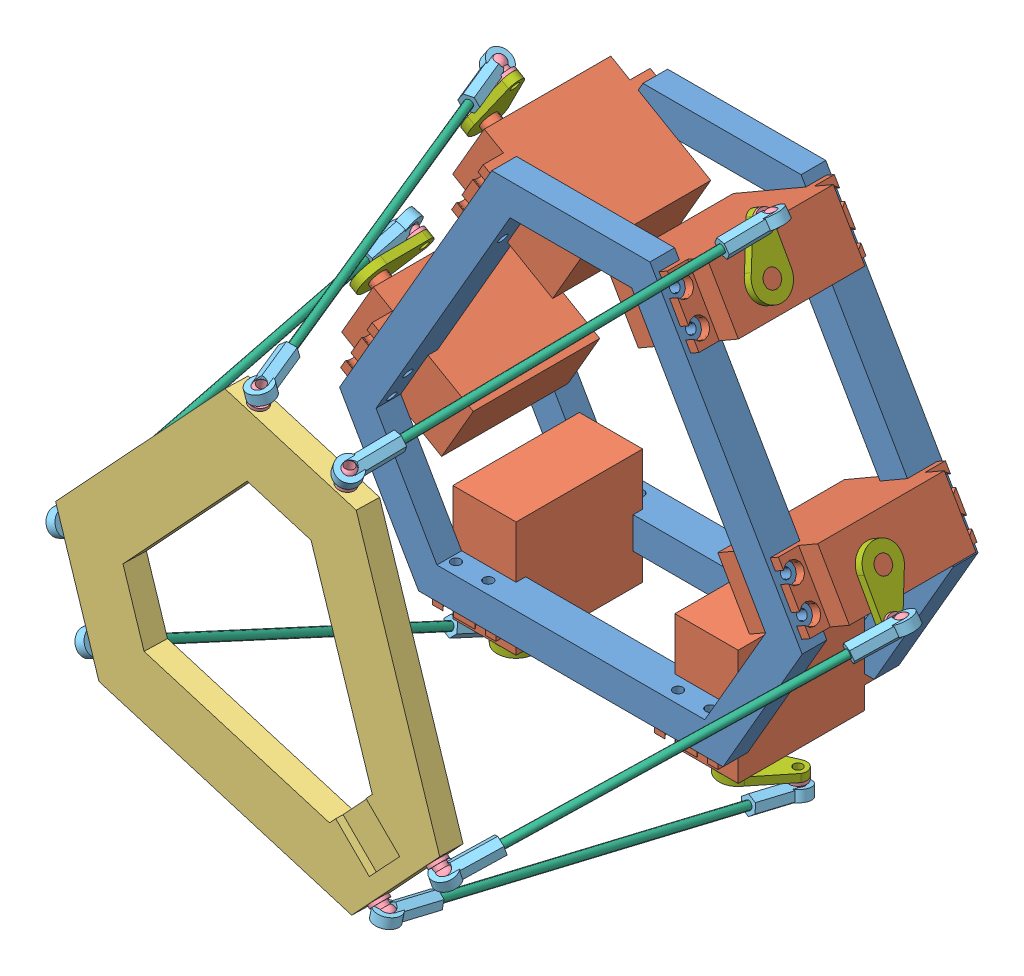
SolidWorks assembly 史都華平台, configuration Default. Lengths in mm.
Overall size (184.22 189.98 155.27).
45 component instances, 7 part files, 100 mates.
Components (placement in the parent):
- 底座-1: 底座 [Default] at (0 0 -7.8) size (146.24 126.65 10.8)
- MG996伺服-1: MG996伺服 [Default] at (-70.2711 11.5881 0) x (0 0 1) z (-0.5 -0.866025 0) size (52.8 43.1 20)
- MG996伺服-2: MG996伺服 [Default] at (-35.1711 72.3831 0) x (0 0 1) z (-0.5 -0.866025 0) size (52.8 43.1 20)
- MG996伺服-3: MG996伺服 [Default] at (-45.1 -66.6506 0) x (0 0 1) z (1 0 0) size (52.8 43.1 20)
- MG996伺服-4: MG996伺服 [Default] at (45.1711 55.0626 0) x (0 0 1) z (-0.5 0.866025 0) size (52.8 43.1 20)
- MG996伺服-5: MG996伺服 [Default] at (80.2711 -5.7324 0) x (0 0 1) z (-0.5 0.866025 0) size (52.8 43.1 20)
- MG996伺服-6: MG996伺服 [Default] at (25.1 -66.6506 0) x (0 0 1) z (1 0 0) size (52.8 43.1 20)
- 平台-1: 平台 [Default] at (-6.0309 -2.8399 134.3888) x (0.972446 -0.227731 0.049864) z (-0.058719 -0.032271 0.997753) size (131.62 113.99 7)
- ball-1: ball [預設] at (32.3885 -59.6857 138.319) x (-0.683773 -0.729623 -0.010231) z (-0.022177 0.006764 0.999731) size (5.5 5.98 5.5)
- ball-2: ball [預設] at (52.8367 -37.8175 140.2297) x (-0.683771 -0.729624 -0.01032) z (-0.022237 0.0067 0.99973) size (5.5 5.98 5.5)
- ball-3: ball [預設] at (-74.5583 -7.9836 133.6974) x (-0.289585 0.95713 -0.006457) z (-0.064619 -0.012819 0.997828) size (5.5 5.98 5.5)
- ball-4: ball [預設] at (-65.8331 -36.6838 133.2826) x (-0.289584 0.957131 -0.006467) z (-0.064621 -0.01281 0.997828) size (5.5 5.98 5.5)
- ball-5: ball [預設] at (23.4606 58.8108 141.6263) x (0.97376 -0.226674 0.020258) z (-0.029859 -0.03901 0.998793) size (5.5 5.98 5.5)
- ball-6: ball [預設] at (-5.7127 65.6427 140.1304) x (0.973786 -0.22664 0.019374) z (-0.028998 -0.03921 0.99881) size (5.5 5.98 5.5)
- balljoint-1: balljoint [預設] at (-5.7127 65.6427 140.1304) x (0.943108 0.163018 -0.289781) z (-0.116948 0.978506 0.169849) size (7.4 18 5.54)
- linkage-1: linkage [預設] at (-39.7314 79.447 37.1806) x (-0.48946 -0.870866 0.044965) z (0.311241 -0.126297 0.941901) size (2.5 2.5 100)
- balljoint-2: balljoint [預設] at (-74.5583 -7.9836 133.6974) x (-0.430412 0.885429 0.17539) z (-0.900005 -0.435794 -0.008603) size (7.4 18 5.54)
- balljoint-3: balljoint [預設] at (23.4606 58.8108 141.6263) x (0.87245 -0.485501 0.055845) z (0.460707 0.855206 0.237429) size (7.4 18 5.54)
- balljoint-4: balljoint [預設] at (-65.8331 -36.6838 133.2826) x (-0.46452 0.801773 -0.376008) z (-0.871059 -0.490211 0.030816) size (7.4 18 5.54)
- balljoint-5: balljoint [預設] at (32.3885 -59.6857 138.319) x (-0.989657 0.070843 -0.124743) z (-0.088052 -0.986463 0.138341) size (7.4 18 5.54)
- balljoint-6: balljoint [預設] at (52.8367 -37.8175 140.2297) x (0.945095 -0.039974 0.324342) z (-0.058965 0.955342 0.289561) size (7.4 18 5.54)
- linkage-2: linkage [預設] at (-82.0799 9.6743 26.0957) x (0.996516 0.057736 -0.060184) z (0.068817 -0.161555 0.984461) size (2.5 2.5 100)
- linkage-3: linkage [預設] at (41.28 78.6396 35.6273) x (0.69636 -0.717487 -0.017154) z (-0.163031 -0.181416 0.969798) size (2.5 2.5 100)
- linkage-4: linkage [預設] at (-48.3871 -74.0468 32.0594) x (-0.561816 0.739932 -0.36995) z (-0.159616 0.341839 0.926104) size (2.5 2.5 100)
- linkage-5: linkage [預設] at (87.9692 -5.8159 41.8016) x (0.036207 0.946503 0.320657) z (-0.321432 -0.292787 0.900532) size (2.5 2.5 100)
- linkage-6: linkage [預設] at (44.7671 -75.8505 30.9321) x (0.568772 -0.801151 0.186159) z (-0.113253 0.147894 0.982497) size (2.5 2.5 100)
- arm-1: arm [預設] at (35.1 -73.2506 30) x (0.794098 0 -0.607789) z (0 1 0) size (22.25 12 2.5)
- arm-2: arm [預設] at (-45.8869 67.0228 30) x (0.496568 0.86008 -0.116972) z (0.866025 -0.5 0) size (22.25 12 2.5)
- arm-3: arm [預設] at (-35.1 -73.2506 30) x (-0.874272 0 -0.485436) z (0 1 0) size (22.25 12 2.5)
- arm-4: arm [預設] at (45.8869 67.0228 30) x (-0.483962 0.838246 -0.251245) z (-0.866025 -0.5 0) size (22.25 12 2.5)
- arm-5: arm [預設] at (-80.9869 6.2278 30) x (0.126645 0.219355 -0.967391) z (0.866025 -0.5 0) size (22.25 12 2.5)
- arm-6: arm [預設] at (80.9869 6.2278 30) x (0.483624 -0.837662 0.25383) z (-0.866025 -0.5 0) size (22.25 12 2.5)
- ball-7: ball [預設] at (90.9586 -3.093 33.4267) x (0.488505 -0.846116 -0.213193) z (0.106596 -0.18463 0.97701) size (5.5 5.98 5.5)
- ball-8: ball [預設] at (42.7961 80.3268 26.6082) x (-0.228737 0.396183 -0.889223) z (0.444612 -0.77009 -0.457473) size (5.5 5.98 5.5)
- ball-9: ball [預設] at (45.8203 -77.2259 21.7948) x (0.837169 0 0.546944) z (0.546944 0 -0.837169) size (5.5 5.98 5.5)
- ball-10: ball [預設] at (-46.9027 -77.2259 23.4466) x (-0.837169 0 -0.546944) z (-0.546944 0 0.837169) size (5.5 5.98 5.5)
- ball-11: ball [預設] at (-42.626 80.6215 28.4209) x (0.5 0.866025 0) z (0 0 1) size (5.5 5.98 5.5)
- ball-12: ball [預設] at (-82.7199 11.1768 16.9402) x (0.5 0.866025 0) z (0 0 1) size (5.5 5.98 5.5)
- balljoint-8: balljoint [預設] at (-82.7199 11.1768 16.9402) x (0.422128 0.898825 0.117994) z (0.903921 -0.407449 -0.130051) size (7.4 18 5.54)
- balljoint-9: balljoint [預設] at (-42.626 80.6215 28.4209) x (-0.785166 0.524202 0.329738) z (0.535391 0.842177 -0.063989) size (7.4 18 5.54)
- balljoint-10: balljoint [預設] at (-46.9027 -77.2259 23.4466) x (0.949004 0.311499 0.048583) z (0.271873 -0.886631 0.374127) size (7.4 18 5.54)
- balljoint-12: balljoint [預設] at (45.8203 -77.2259 21.7948) x (0.979291 0.183636 0.085241) z (0.167816 -0.971805 0.165629) size (7.4 18 5.54)
- balljoint-13: balljoint [預設] at (42.7961 80.3268 26.6082) x (0.842565 0.485816 0.232522) z (0.513327 -0.855027 -0.073652) size (7.4 18 5.54)
- balljoint-14: balljoint [預設] at (90.9586 -3.093 33.4267) x (0.838407 0.354071 0.414376) z (0.440176 -0.888206 -0.131665) size (7.4 18 5.54)
- 底座-2: 底座 [Default] at (0 0 47.8) x (0.5 0.866025 0) z (0 0 -1) size (146.24 126.65 10.8)
Mates (geometry in assembly coordinates):
- 同軸心6: concentric aligned: cylinder of 底座-1 through (-23.6686 48.3061 -3.9) axis (-0.866025 0.5 0) radius 1.5; cylinder of MG996伺服-2 through (-11.1112 41.0561 -3.9) axis (-0.866025 0.5 0) radius 3
- 同軸心7: concentric aligned: cylinder of 底座-1 through (-18.5686 57.1395 -3.9) axis (-0.866025 0.5 0) radius 1.5; cylinder of MG996伺服-2 through (-6.0112 49.8895 -3.9) axis (-0.866025 0.5 0) radius 3
- 重合/共線/共點16: coincident anti-aligned: plane of 底座-1 through (-73.1218 -13.3494 0) normal (-0.866025 0.5 0); plane of MG996伺服-2 through (-36.5109 50.0626 -6.4) normal (0.866025 -0.5 0)
- 同軸心10: concentric aligned: cylinder of 底座-1 through (-53.6686 -3.6554 -3.9) axis (-0.866025 0.5 0) radius 1.5; cylinder of MG996伺服-1 through (-41.1112 -10.9054 -3.9) axis (-0.866025 0.5 0) radius 3
- 同軸心11: concentric aligned: cylinder of 底座-1 through (-58.7686 -12.4889 -3.9) axis (-0.866025 0.5 0) radius 1.5; cylinder of MG996伺服-1 through (-46.2112 -19.7389 -3.9) axis (-0.866025 0.5 0) radius 3
- 重合/共線/共點17: coincident anti-aligned: plane of 底座-1 through (-73.1218 -13.3494 0) normal (-0.866025 0.5 0); plane of MG996伺服-1 through (-71.6109 -10.7324 -6.4) normal (0.866025 -0.5 0)
- 同軸心12: concentric aligned: cylinder of 底座-1 through (18.5686 57.1395 -3.9) axis (0.866025 0.5 0) radius 1.5; cylinder of MG996伺服-4 through (6.0112 49.8895 -3.9) axis (0.866025 0.5 0) radius 3
- 同軸心14: concentric aligned: cylinder of 底座-1 through (23.6686 48.3061 -3.9) axis (0.866025 0.5 0) radius 1.5; cylinder of MG996伺服-4 through (11.1112 41.0561 -3.9) axis (0.866025 0.5 0) radius 3
- 重合/共線/共點18: coincident anti-aligned: plane of 底座-1 through (25 70 0) normal (0.866025 0.5 0); plane of MG996伺服-4 through (26.5109 67.3831 -6.4) normal (-0.866025 -0.5 0)
- 同軸心15: concentric aligned: cylinder of 底座-1 through (-30 -44.6506 -3.9) axis (0 -1 0) radius 1.5; cylinder of MG996伺服-3 through (-30 -30.1506 -3.9) axis (0 -1 0) radius 3
- 同軸心16: concentric aligned: circle of 底座-1; cylinder of MG996伺服-3 through (-40.2 -30.1506 -3.9) axis (0 -1 0) radius 3
- 重合/共線/共點19: coincident anti-aligned: plane of 底座-1 through (48.1218 -56.6506 0) normal (0 -1 0); plane of MG996伺服-3 through (-25.1 -56.6506 -6.4) normal (0 1 0)
- 同軸心17: concentric aligned: cylinder of 底座-1 through (53.6686 -3.6554 -3.9) axis (0.866025 0.5 0) radius 1.5; cylinder of MG996伺服-5 through (41.1112 -10.9054 -3.9) axis (0.866025 0.5 0) radius 3
- 同軸心18: concentric aligned: cylinder of 底座-1 through (58.7686 -12.4889 -3.9) axis (0.866025 0.5 0) radius 1.5; cylinder of MG996伺服-5 through (46.2112 -19.7389 -3.9) axis (0.866025 0.5 0) radius 3
- 重合/共線/共點20: coincident anti-aligned: plane of 底座-1 through (25 70 0) normal (0.866025 0.5 0); plane of MG996伺服-5 through (61.6109 6.5881 -6.4) normal (-0.866025 -0.5 0)
- 同軸心19: concentric aligned: cylinder of 底座-1 through (40.2 -44.6506 -3.9) axis (0 -1 0) radius 1.5; circle of MG996伺服-6
- 同軸心20: concentric aligned: cylinder of 底座-1 through (30 -44.6506 -3.9) axis (0 -1 0) radius 1.5; cylinder of MG996伺服-6 through (30 -30.1506 -3.9) axis (0 -1 0) radius 3
- 重合/共線/共點24: coincident anti-aligned: plane of 底座-1 through (48.1218 -56.6506 0) normal (0 -1 0); plane of MG996伺服-6 through (45.1 -56.6506 -6.4) normal (0 1 0)
- 重合/共線/共點28: coincident: point of 底座-1; point of assembly
- 平行(R)1: parallel anti-aligned: plane of 底座-1 through (0 0 -7.8) normal (0 0 -1); plane of assembly through (0 0 0) normal (0 0 1)
- 重合/共線/共點30: coincident: line of 底座-1 through (0 0 0) axis (0 1 0); plane of assembly
- 同軸心21: concentric anti-aligned: cylinder of 平台-1 through (20.7368 -48.7616 137.9866) axis (0.729358 -0.683816 0.020806) radius 1.5; cylinder of ball-1 through (33.8652 -61.0703 138.3612) axis (-0.729358 0.683816 -0.020806) radius 1.5
- 重合/共線/共點31: coincident anti-aligned: plane of 平台-1 through (54.8438 -29.745 144.1168) normal (0.729358 -0.683816 0.020806); plane of ball-1 through (29.4891 -56.9674 138.2363) normal (-0.729358 0.683816 -0.020806)
- 同軸心22: concentric anti-aligned: cylinder of 平台-1 through (41.185 -26.8934 139.8974) axis (0.729358 -0.683816 0.020806) radius 1.5; cylinder of ball-2 through (54.3134 -39.202 140.2719) axis (-0.729358 0.683816 -0.020806) radius 1.5
- 同軸心23: concentric anti-aligned: cylinder of 平台-1 through (-59.3024 -3.3608 134.7447) axis (-0.954969 -0.289373 -0.06556) radius 1.5; cylinder of ball-3 through (-76.4918 -8.5695 133.5646) axis (0.954969 0.289373 0.06556) radius 1.5
- 重合/共線/共點33: coincident anti-aligned: plane of 平台-1 through (-60.0611 -42.8214 136.9316) normal (-0.954969 -0.289373 -0.06556); plane of ball-3 through (-70.762 -6.8333 133.958) normal (0.954969 0.289373 0.06556)
- 同軸心24: concentric anti-aligned: cylinder of 平台-1 through (-50.5772 -32.061 134.3299) axis (-0.954969 -0.289373 -0.06556) radius 1.5; cylinder of ball-4 through (-67.7666 -37.2697 133.1498) axis (0.954969 0.289373 0.06556) radius 1.5
- 重合/共線/共點34: coincident anti-aligned: plane of 平台-1 through (-60.0611 -42.8214 136.9316) normal (-0.954969 -0.289373 -0.06556); plane of ball-4 through (-62.0368 -35.5335 133.5432) normal (0.954969 0.289373 0.06556)
- 同軸心25: concentric anti-aligned: cylinder of 平台-1 through (-9.3169 50.0958 139.4154) axis (0.225611 0.973189 0.044754) radius 1.5; cylinder of ball-6 through (-5.256 67.6132 140.221) axis (-0.225611 -0.973189 -0.044754) radius 1.5
- 同軸心26: concentric anti-aligned: cylinder of 平台-1 through (19.8564 43.2638 140.9113) axis (0.225611 0.973189 0.044754) radius 1.5; cylinder of ball-5 through (23.9174 60.7812 141.7169) axis (-0.225611 -0.973189 -0.044754) radius 1.5
- 重合/共線/共點35: coincident anti-aligned: plane of 平台-1 through (-14.1085 63.3691 143.0706) normal (0.225611 0.973189 0.044754); plane of ball-6 through (-6.6096 61.774 139.9525) normal (-0.225611 -0.973189 -0.044754)
- 重合/共線/共點36: coincident anti-aligned: plane of 平台-1 through (-14.1085 63.3691 143.0706) normal (0.225611 0.973189 0.044754); plane of ball-5 through (22.5638 54.9421 141.4484) normal (-0.225611 -0.973189 -0.044754)
- 重合/共線/共點37: coincident: unknown of ?
- 重合/共線/共點38: coincident: unknown of ?
- 平行(R)2: parallel aligned: plane of 底座-1 through (0 0 0) normal (0 0 1); plane of 平台-1
- 平行(R)3: parallel aligned: line of 底座-1 through (0 0 0) axis (0 1 0); line of 平台-1 through (0 0 172.5355) axis (0 1 0)
- 同軸心27: concentric: sphere of ball-6; sphere of balljoint-1
- 同軸心28: concentric aligned: cylinder of balljoint-1 through (-8.6073 66.8173 131.3707) axis (-0.311241 0.126297 -0.941901) radius 1.1; cylinder of linkage-1 through (-8.6073 66.8173 131.3707) axis (-0.311241 0.126297 -0.941901) radius 1.25
- 重合/共線/共點39: coincident anti-aligned: plane of balljoint-1 through (-8.6073 66.8173 131.3707) normal (-0.311241 0.126297 -0.941901); plane of linkage-1 through (-8.6073 66.8173 131.3707) normal (0.311241 -0.126297 0.941901)
- 同軸心29: concentric: sphere of ball-5; sphere of balljoint-3
- 同軸心30: concentric: sphere of ball-2; sphere of balljoint-6
- 同軸心31: concentric: sphere of ball-1; sphere of balljoint-5
- 同軸心32: concentric: sphere of ball-3; sphere of balljoint-2
- 同軸心33: concentric: sphere of ball-4; sphere of balljoint-4
- 重合/共線/共點40: coincident anti-aligned: plane of balljoint-3 through (24.9768 60.498 132.6072) normal (0.163031 0.181416 -0.969798); plane of linkage-3 through (24.9768 60.498 132.6072) normal (-0.163031 -0.181416 0.969798)
- 重合/共線/共點41: coincident anti-aligned: plane of balljoint-2 through (-75.1983 -6.4812 124.5419) normal (-0.068817 0.161555 -0.984461); plane of linkage-2 through (-75.1983 -6.4812 124.5419) normal (0.068817 -0.161555 0.984461)
- 重合/共線/共點42: coincident anti-aligned: plane of balljoint-4 through (-64.3487 -39.8629 124.6698) normal (0.159616 -0.341839 -0.926104); plane of linkage-4 through (-64.3487 -39.8629 124.6698) normal (-0.159616 0.341839 0.926104)
- 重合/共線/共點43: coincident anti-aligned: plane of balljoint-5 through (33.4417 -61.0612 129.1818) normal (0.113253 -0.147894 -0.982497); plane of linkage-6 through (33.4417 -61.0612 129.1818) normal (-0.113253 0.147894 0.982497)
- 重合/共線/共點44: coincident anti-aligned: plane of balljoint-6 through (55.826 -35.0946 131.8548) normal (0.321432 0.292787 -0.900532); plane of linkage-5 through (55.826 -35.0946 131.8548) normal (-0.321432 -0.292787 0.900532)
- 同軸心39: concentric anti-aligned: cylinder of MG996伺服-5 through (80.9869 6.2278 30) axis (-0.866025 -0.5 0) radius 2.7; cylinder of arm-6 through (78.8218 4.9778 30) axis (0.866025 0.5 0) radius 2.6
- 重合/共線/共點45: coincident aligned: plane of MG996伺服-5 through (80.9869 6.2278 30) normal (0.866025 0.5 0); plane of arm-6 through (80.9869 6.2278 30) normal (0.866025 0.5 0)
- 同軸心40: concentric anti-aligned: cylinder of MG996伺服-3 through (-35.1 -73.2506 30) axis (0 1 0) radius 2.7; cylinder of arm-3 through (-35.1 -70.7506 30) axis (0 -1 0) radius 2.6
- 重合/共線/共點46: coincident aligned: plane of MG996伺服-3 through (-35.1 -73.2506 30) normal (0 -1 0); plane of arm-3 through (-35.1 -73.2506 30) normal (0 -1 0)
- 同軸心41: concentric anti-aligned: cylinder of MG996伺服-6 through (35.1 -73.2506 30) axis (0 1 0) radius 2.7; cylinder of arm-1 through (35.1 -70.7506 30) axis (0 -1 0) radius 2.6
- 重合/共線/共點47: coincident aligned: circle of MG996伺服-6; plane of arm-1 through (35.1 -73.2506 30) normal (0 -1 0)
- 同軸心42: concentric anti-aligned: cylinder of MG996伺服-1 through (-80.9869 6.2278 30) axis (0.866025 -0.5 0) radius 2.7; cylinder of arm-5 through (-78.8218 4.9778 30) axis (-0.866025 0.5 0) radius 2.6
- 重合/共線/共點48: coincident aligned: plane of MG996伺服-1 through (-80.9869 6.2278 30) normal (-0.866025 0.5 0); plane of arm-5 through (-80.9869 6.2278 30) normal (-0.866025 0.5 0)
- 同軸心43: concentric anti-aligned: cylinder of MG996伺服-2 through (-45.8869 67.0228 30) axis (0.866025 -0.5 0) radius 2.7; cylinder of arm-2 through (-43.7218 65.7728 30) axis (-0.866025 0.5 0) radius 2.6
- 重合/共線/共點49: coincident aligned: plane of MG996伺服-2 through (-45.8869 67.0228 30) normal (-0.866025 0.5 0); plane of arm-2 through (-45.8869 67.0228 30) normal (-0.866025 0.5 0)
- 同軸心44: concentric anti-aligned: cylinder of MG996伺服-4 through (45.8869 67.0228 30) axis (-0.866025 -0.5 0) radius 2.7; cylinder of arm-4 through (43.7218 65.7728 30) axis (0.866025 0.5 0) radius 2.6
- 重合/共線/共點50: coincident aligned: plane of MG996伺服-4 through (45.8869 67.0228 30) normal (0.866025 0.5 0); plane of arm-4 through (45.8869 67.0228 30) normal (0.866025 0.5 0)
- 同軸心45: concentric anti-aligned: cylinder of arm-6 through (85.3508 -6.3306 33.4267) axis (0.866025 0.5 0) radius 1.4; cylinder of ball-7 through (92.712 -2.0806 33.4267) axis (-0.866025 -0.5 0) radius 1.5
- 重合/共線/共點51: coincident anti-aligned: plane of arm-6 through (80.9869 6.2278 30) normal (0.866025 0.5 0); plane of ball-7 through (87.5158 -5.0806 33.4267) normal (-0.866025 -0.5 0)
- 同軸心46: concentric anti-aligned: cylinder of arm-1 through (45.8203 -70.7506 21.7948) axis (0 -1 0) radius 1.4; cylinder of ball-9 through (45.8203 -79.2506 21.7948) axis (0 1 0) radius 1.5
- 重合/共線/共點52: coincident anti-aligned: plane of arm-1 through (35.1 -73.2506 30) normal (0 -1 0); plane of ball-9 through (45.8203 -73.2506 21.7948) normal (0 1 0)
- 同軸心47: concentric anti-aligned: cylinder of arm-3 through (-46.9027 -70.7506 23.4466) axis (0 -1 0) radius 1.4; cylinder of ball-10 through (-46.9027 -79.2506 23.4466) axis (0 1 0) radius 1.5
- 重合/共線/共點53: coincident anti-aligned: plane of arm-3 through (-35.1 -73.2506 30) normal (0 -1 0); plane of ball-10 through (-46.9027 -73.2506 23.4466) normal (0 1 0)
- 同軸心48: concentric anti-aligned: cylinder of arm-4 through (37.1884 77.0891 26.6082) axis (0.866025 0.5 0) radius 1.4; cylinder of ball-8 through (44.5496 81.3391 26.6082) axis (-0.866025 -0.5 0) radius 1.5
- 重合/共線/共點55: coincident anti-aligned: plane of arm-4 through (45.8869 67.0228 30) normal (0.866025 0.5 0); plane of ball-8 through (39.3534 78.3391 26.6082) normal (-0.866025 -0.5 0)
- 同軸心49: concentric anti-aligned: cylinder of arm-2 through (-37.0182 77.3839 28.4209) axis (-0.866025 0.5 0) radius 1.4; cylinder of ball-11 through (-44.3794 81.6339 28.4209) axis (0.866025 -0.5 0) radius 1.5
- 重合/共線/共點56: coincident anti-aligned: plane of arm-2 through (-45.8869 67.0228 30) normal (-0.866025 0.5 0); plane of ball-11 through (-39.1832 78.6339 28.4209) normal (0.866025 -0.5 0)
- 同軸心50: concentric anti-aligned: cylinder of arm-5 through (-77.1121 7.9391 16.9402) axis (-0.866025 0.5 0) radius 1.4; cylinder of ball-12 through (-84.4734 12.1891 16.9402) axis (0.866025 -0.5 0) radius 1.5
- 重合/共線/共點57: coincident anti-aligned: plane of arm-5 through (-80.9869 6.2278 30) normal (-0.866025 0.5 0); plane of ball-12 through (-79.2772 9.1891 16.9402) normal (0.866025 -0.5 0)
- 同軸心53: concentric: sphere of ball-9; sphere of balljoint-12
- 同軸心55: concentric: sphere of ball-10; sphere of balljoint-10
- 同軸心57: concentric: sphere of ball-12; sphere of balljoint-8
- 同軸心59: concentric: sphere of ball-11; sphere of balljoint-9
- 同軸心61: concentric: sphere of ball-8; sphere of balljoint-13
- 同軸心64: concentric: sphere of ball-7; sphere of balljoint-14
- 重合/共線/共點60: coincident anti-aligned: plane of linkage-2 through (-82.0799 9.6743 26.0957) normal (-0.068817 0.161555 -0.984461); plane of balljoint-8 through (-82.0799 9.6743 26.0957) normal (0.068817 -0.161555 0.984461)
- 重合/共線/共點61: coincident anti-aligned: plane of linkage-1 through (-39.7314 79.447 37.1806) normal (-0.311241 0.126297 -0.941901); plane of balljoint-9 through (-39.7314 79.447 37.1806) normal (0.311241 -0.126297 0.941901)
- 重合/共線/共點62: coincident anti-aligned: plane of linkage-5 through (87.9692 -5.8159 41.8016) normal (0.321432 0.292787 -0.900532); plane of balljoint-14 through (87.9692 -5.8159 41.8016) normal (-0.321432 -0.292787 0.900532)
- 重合/共線/共點65: coincident anti-aligned: plane of linkage-4 through (-48.3871 -74.0468 32.0594) normal (0.159616 -0.341839 -0.926104); plane of balljoint-10 through (-48.3871 -74.0468 32.0594) normal (-0.159616 0.341839 0.926104)
- 重合/共線/共點66: coincident anti-aligned: plane of 平台-1 through (54.8438 -29.745 144.1168) normal (0.729358 -0.683816 0.020806); plane of ball-2 through (49.9373 -35.0991 140.147) normal (-0.729358 0.683816 -0.020806)
- 重合/共線/共點67: coincident anti-aligned: plane of linkage-6 through (44.7671 -75.8505 30.9321) normal (0.113253 -0.147894 -0.982497); plane of balljoint-12 through (44.7671 -75.8505 30.9321) normal (-0.113253 0.147894 0.982497)
- 重合/共線/共點68: coincident anti-aligned: plane of linkage-3 through (41.28 78.6396 35.6273) normal (0.163031 0.181416 -0.969798); plane of balljoint-13 through (41.28 78.6396 35.6273) normal (-0.163031 -0.181416 0.969798)
- 同軸心66: concentric anti-aligned: cylinder of linkage-1 through (-8.6073 66.8173 131.3707) axis (-0.311241 0.126297 -0.941901) radius 1.25; cylinder of balljoint-9 through (-39.7314 79.447 37.1806) axis (0.311241 -0.126297 0.941901) radius 1.1
- 同軸心67: concentric anti-aligned: cylinder of linkage-2 through (-75.1983 -6.4812 124.5419) axis (-0.068817 0.161555 -0.984461) radius 1.25; cylinder of balljoint-8 through (-82.0799 9.6743 26.0957) axis (0.068817 -0.161555 0.984461) radius 1.1
- 同軸心68: concentric anti-aligned: cylinder of linkage-4 through (-64.3487 -39.8629 124.6698) axis (0.159616 -0.341839 -0.926104) radius 1.25; cylinder of balljoint-10 through (-48.3871 -74.0468 32.0594) axis (-0.159616 0.341839 0.926104) radius 1.1
- 同軸心69: concentric anti-aligned: cylinder of linkage-6 through (33.4417 -61.0612 129.1818) axis (0.113253 -0.147894 -0.982497) radius 1.25; cylinder of balljoint-12 through (44.7671 -75.8505 30.9321) axis (-0.113253 0.147894 0.982497) radius 1.1
- 同軸心70: concentric anti-aligned: cylinder of linkage-5 through (55.826 -35.0946 131.8548) axis (0.321432 0.292787 -0.900532) radius 1.25; cylinder of balljoint-14 through (87.9692 -5.8159 41.8016) axis (-0.321432 -0.292787 0.900532) radius 1.1
- 同軸心71: concentric anti-aligned: cylinder of linkage-3 through (24.9768 60.498 132.6072) axis (0.163031 0.181416 -0.969798) radius 1.25; cylinder of balljoint-13 through (41.28 78.6396 35.6273) axis (-0.163031 -0.181416 0.969798) radius 1.1
- 同軸心72: concentric aligned: cylinder of balljoint-4 through (-64.3487 -39.8629 124.6698) axis (0.159616 -0.341839 -0.926104) radius 1.1; cylinder of linkage-4 through (-64.3487 -39.8629 124.6698) axis (0.159616 -0.341839 -0.926104) radius 1.25
- 同軸心73: concentric aligned: cylinder of balljoint-6 through (55.826 -35.0946 131.8548) axis (0.321432 0.292787 -0.900532) radius 1.1; cylinder of linkage-5 through (55.826 -35.0946 131.8548) axis (0.321432 0.292787 -0.900532) radius 1.25
- 同軸心74: concentric aligned: cylinder of balljoint-5 through (33.4417 -61.0612 129.1818) axis (0.113253 -0.147894 -0.982497) radius 1.1; cylinder of linkage-6 through (33.4417 -61.0612 129.1818) axis (0.113253 -0.147894 -0.982497) radius 1.25
- 同軸心75: concentric aligned: cylinder of balljoint-3 through (24.9768 60.498 132.6072) axis (0.163031 0.181416 -0.969798) radius 1.1; cylinder of linkage-3 through (24.9768 60.498 132.6072) axis (0.163031 0.181416 -0.969798) radius 1.25
- 同軸心76: concentric aligned: cylinder of balljoint-2 through (-75.1983 -6.4812 124.5419) axis (-0.068817 0.161555 -0.984461) radius 1.1; cylinder of linkage-2 through (-75.1983 -6.4812 124.5419) axis (-0.068817 0.161555 -0.984461) radius 1.25
- 同軸心79: concentric aligned: cylinder of MG996伺服-4 through (6.0112 49.8895 43.9) axis (0.866025 0.5 0) radius 3; cylinder of 底座-2 through (18.5686 57.1395 43.9) axis (0.866025 0.5 0) radius 1.5
- 同軸心80: concentric aligned: cylinder of MG996伺服-5 through (46.2112 -19.7389 43.9) axis (0.866025 0.5 0) radius 3; cylinder of 底座-2 through (58.7686 -12.4889 43.9) axis (0.866025 0.5 0) radius 1.5
- 同軸心81: concentric aligned: cylinder of MG996伺服-6 through (40.2 -30.1506 43.9) axis (0 -1 0) radius 3; cylinder of 底座-2 through (40.2 -44.6506 43.9) axis (0 -1 0) radius 1.5
